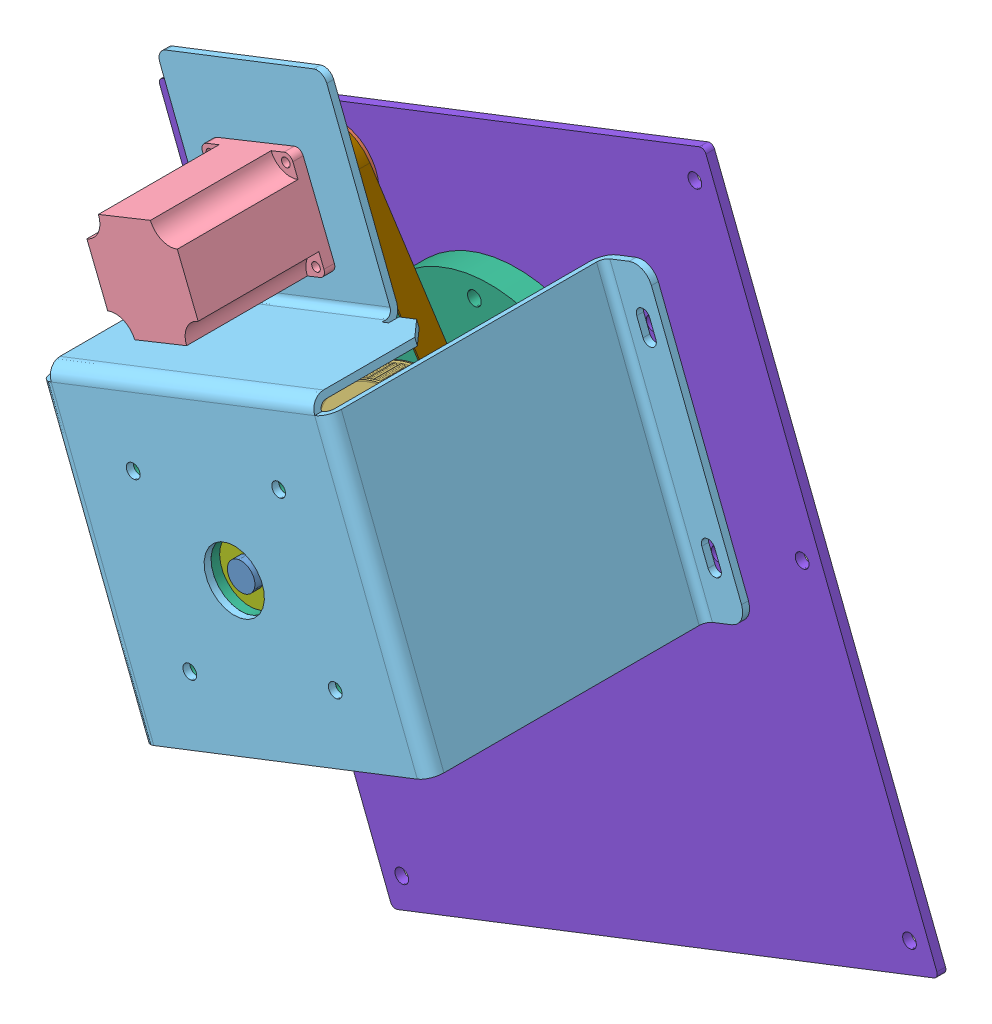
SolidWorks assembly Assem1, configuration Default. Lengths in mm.
Overall size (480.38 518.97 211).
11 component instances, 9 part files, 19 mates.
Components (placement in the parent):
- Rotation Axis-1: Rotation Axis [Default] at (-63.5739 107.0716 21.4277) x (-0.094919 -0.995485 0) z (0 0 1) size (170 170 207)
- Synchoronous Pulley-1: Synchoronous Pulley [Default] at (-66.9973 226.6829 137.4277) x (0.051075 0.998695 0) z (0 0 1) size (47.12 47.12 34.01)
- Synchoronous Pulley2-1: Synchoronous Pulley2 [Default] at (-13.7996 102.3257 136.1777) x (0.527027 0.849849 0) z (0 0 1) size (96.89 96.89 29.68)
- Nema 23 401-1: Nema 23 401 [Inserir número] at (-66.9973 226.6829 164.4277) x (0 0 -1) z (-0.371877 0.928282 0) size (96.5 56.5 56.5)
- motor Base-1: motor Base [Default] at (-13.7996 102.3257 236.4277) x (-0.837065 0.547104 0) z (0 0 1) size (321.61 294.91 164)
- motor Base circ-1: motor Base circ [Default] at (-13.7996 102.3257 250.4277) x (-0.362936 0.931814 0) z (0 0 -1) size (150 150 16)
- DIN 628 SKF - SKF QJ 212-1: DIN 628 SKF - SKF QJ 212 [Default] at (-13.7996 102.3257 220.4277) x (0.299259 0.954172 0) z (0 0 1) size (35 35 11)
- base_top-1: base_top [Default] at (4.3472 55.735 76.4277) x (-0.931814 -0.362936 0) z (0 0 -1) size (340 375 5)
- DIN 628 SKF - SKF QJ 212-2: DIN 628 SKF - SKF QJ 212 [Default] at (-13.7996 102.3257 92.4277) x (-0.923398 0.383844 0) z (0 0 -1) size (35 35 11)
- motor Base circ-2: motor Base circ [Default] at (-13.7996 102.3257 106.4277) x (0.604108 0.796903 0) z (0 0 -1) size (150 150 16)
- belt-2: belt [Default] at (-14.2515 101.9902 136.9277) x (0.389584 -0.920991 0) z (0 0 1) size (208.01 96.49 16)
Mates (geometry in assembly coordinates):
- Concentric13: concentric aligned: cylinder of Nema 23 401-1 through (-66.9973 226.6829 164.4277) axis (0 0 1) radius 3; circle of motor Base-1
- Coincident8: coincident anti-aligned: plane of Nema 23 401-1 through (-53.5044 258.2117 164.4277) normal (0 0 -1); plane of motor Base-1 through (-38.2954 308.493 164.4277) normal (0 0 1)
- Concentric14: concentric anti-aligned: cylinder of Nema 23 401-1 through (-53.8939 257.3016 240.4277) axis (0 0 -1) radius 2.5; circle of motor Base-1
- Concentric19: concentric anti-aligned: cylinder of DIN 628 SKF - SKF QJ 212-2 through (-13.7996 102.3257 81.4277) axis (0 0 1) radius 17.5; cylinder of motor Base circ-2 through (-13.7996 102.3257 106.4277) axis (0 0 -1) radius 17.5
- GearMate3: gear = 16 : 24 mm: circle of Synchoronous Pulley2-1; circle of Rotation Axis-1
- GearMate4: gear = 1 : 1 mm: circle of Synchoronous Pulley-1; circle of Synchoronous Pulley2-1
- Coincident30: coincident aligned: plane of motor Base circ-1 through (-13.7996 102.3257 220.4277) normal (0 0 -1); plane of DIN 628 SKF - SKF QJ 212-1 through (-13.7996 102.3257 220.4277) normal (0 0 -1)
- Concentric46: concentric aligned: circle of Synchoronous Pulley-1; circle of belt-2
- Concentric47: concentric aligned: cylinder of motor Base circ-1 through (-13.7996 102.3257 250.4277) axis (0 0 -1) radius 17.5; cylinder of DIN 628 SKF - SKF QJ 212-1 through (-13.7996 102.3257 231.4277) axis (0 0 -1) radius 17.5
- Coincident53: coincident anti-aligned: plane of motor Base-1 through (92.3699 55.6776 236.4277) normal (0 0 -1); plane of motor Base circ-1 through (-41.0198 172.2117 236.4277) normal (0 0 1)
- Concentric48: concentric anti-aligned: cylinder of motor Base-1 through (-39.5441 43.732 236.4277) axis (0 0 -1) radius 4; cylinder of motor Base circ-1 through (-39.5441 43.732 236.4277) axis (0 0 1) radius 4
- Coincident54: coincident anti-aligned: circle of DIN 628 SKF - SKF QJ 212-2; circle of motor Base circ-2
- Concentric56: concentric anti-aligned: cylinder of Rotation Axis-1 through (-13.7996 102.3257 29.4277) axis (0 0 1) radius 8; cylinder of DIN 628 SKF - SKF QJ 212-1 through (-13.7996 102.3257 231.4277) axis (0 0 -1) radius 8
- Concentric60: concentric aligned: cylinder of Rotation Axis-1 through (-13.7996 102.3257 29.4277) axis (0 0 1) radius 8; cylinder of DIN 628 SKF - SKF QJ 212-2 through (-13.7996 102.3257 81.4277) axis (0 0 1) radius 8
- Concentric64: concentric anti-aligned: cylinder of Rotation Axis-1 through (-13.7996 102.3257 29.4277) axis (0 0 1) radius 8; cylinder of base_top-1 through (-13.7996 102.3257 69.4565) axis (0 0 -1) radius 20
- Coincident70: coincident anti-aligned: circle of Synchoronous Pulley-1; circle of motor Base-1
- Concentric65: concentric anti-aligned: cylinder of Rotation Axis-1 through (-13.7996 102.3257 29.4277) axis (0 0 1) radius 8; cylinder of motor Base-1 through (-13.7996 102.3257 236.4277) axis (0 0 -1) radius 17.5
- Parallel1: parallel aligned: plane of motor Base-1 through (-121.8901 60.2251 236.4277) normal (-0.931814 -0.362936 0); plane of base_top-1 through (-87.0996 -177.8838 76.4277) normal (-0.931814 -0.362936 0)
- Distance1: distance = 4 mm aligned: plane of base_top-1 through (92.9985 288.265 76.4277) normal (0 0 1); plane of motor Base-1 through (-212.6955 293.3622 80.4277) normal (0 0 1)
